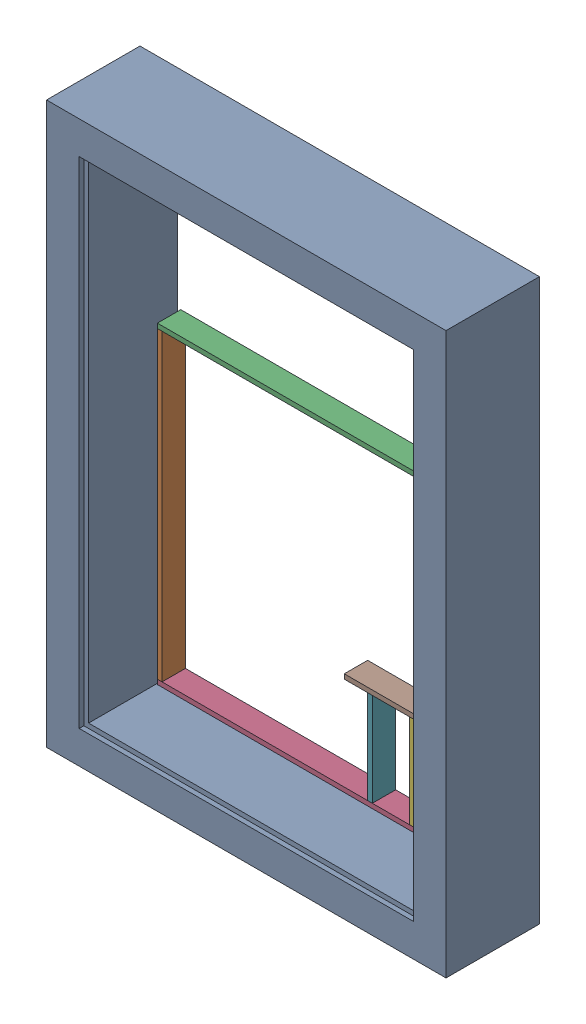
SolidWorks assembly СбОкно1, configuration По умолчанию. Lengths in mm.
Overall size (855 1200 200).
9 component instances, 4 part files, 3 mates.
Components (placement in the parent):
- Окно1-1: Окно1 [По умолчанию] at (-427.5 -279.6829 -200) x (1 0 0) z (0 -1 0) size (855 200 1200)
- СбРамкан-1: СбРамкан [По умолчанию] at (-767.75 -784.6829 -200) size (680 670 50)
  - Брус65-1: Брус65 [По умолчанию] at (0 650 0) x (0 -1 0) z (-1 0 0) size (650 50 10)
  - Брус68SLDPRT-1: Брус68SLDPRT [По умолчанию] at (0 650 0) x (1 0 0) z (0 -1 0) size (680 50 10)
  - Брус68SLDPRT-2: Брус68SLDPRT [По умолчанию] at (0 -10 0) x (1 0 0) z (0 -1 0) size (680 50 10)
  - Брус65-2: Брус65 [По умолчанию] at (670 650 0) x (0 -1 0) z (-1 0 0) size (650 50 10)
  - Брус200-1: Брус200 [По умолчанию] at (550 200 50) x (0 -1 0) z (1 0 0) size (200 50 10)
  - Брус200-2: Брус200 [По умолчанию] at (460 200 50) x (0 -1 0) z (1 0 0) size (200 50 10)
  - Брус200-3: Брус200 [По умолчанию] at (600 200 50) x (-1 0 0) z (0 -1 0) size (200 50 10)
Mates (geometry in assembly coordinates):
- Совпадение4: coincident aligned: plane of Окно1-1 through (-427.5 -279.6829 -200) normal (0 0 -1); plane of СбРамкан-1/Брус65-2 through (-100 -784.6829 -200) normal (0 0 -1)
- Расстояние1: distance = 7.25 mm anti-aligned: plane of СбРамкан-1/Брус65-1 through (-767.75 -784.6829 -200) normal (-1 0 0); plane of Окно1-1 through (-775 240.3171 0) normal (1 0 0)
- Расстояние2: distance = 5 mm anti-aligned: plane of Окно1-1 through (-775 -799.6829 0) normal (0 1 0); plane of СбРамкан-1/Брус68SLDPRT-2 through (-87.75 -794.6829 -200) normal (0 -1 0)
